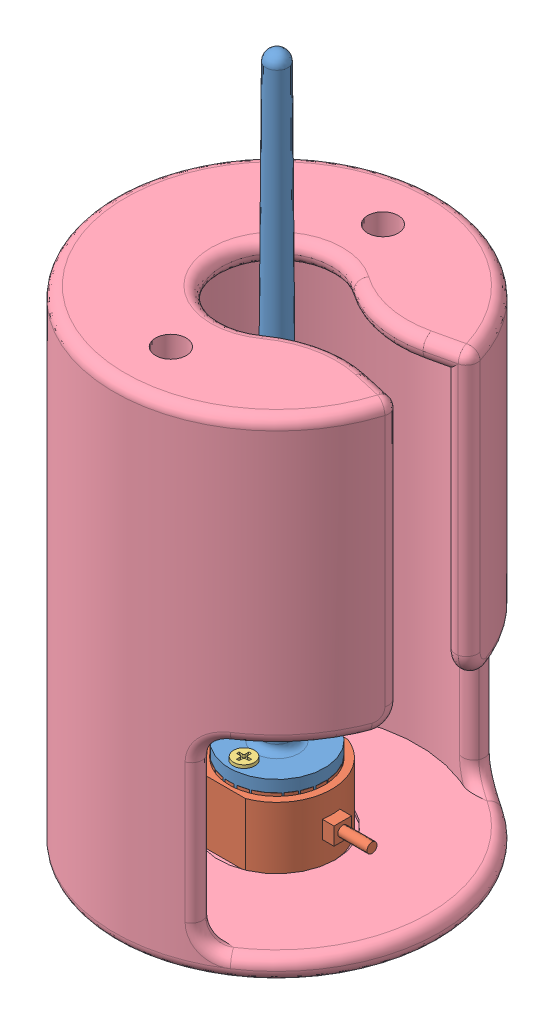
SolidWorks assembly 装配体1, configuration 默认. Lengths in mm.
Overall size (44.5 95.74 44.5).
7 component instances, 4 part files, 13 mates.
Components (placement in the parent):
- press_ indenter-1: press_ indenter [默认] at (-19.629 -24.15 83.9384) size (13 83.94 13)
- press_sensor-1: press_sensor [默认] at (-19.629 -32.75 83.9384) size (20.5 9.05 14)
- cross recessed cheese head screws type a gb-1: cross recessed cheese head screws type a gb [GB_CROSS_SCREWS_TYPE135 M2X5-N] at (-19.629 -21.6729 79.4384) x (0 -1 0) z (-0.546944 0 0.837169) size (5.7 2.98 2.98)
- cross recessed cheese head screws type a gb-2: cross recessed cheese head screws type a gb [GB_CROSS_SCREWS_TYPE135 M2X5-N] at (-19.629 -21.7499 88.4384) x (0 -1 0) z (0 0 1) size (5.7 2.98 2.98)
- press_outer-1: press_outer [默认] at (-19.629 -35.25 83.9384) x (0 0 -1) z (1 0 0) size (44.5 67 44.5)
- cross recessed cheese head screws type a gb-3: cross recessed cheese head screws type a gb [GB_CROSS_SCREWS_TYPE135 M2X5-N] at (-19.629 -35.95 79.4384) x (0 1 0) z (0 0 1) size (5.7 2.98 2.98)
- cross recessed cheese head screws type a gb-5: cross recessed cheese head screws type a gb [GB_CROSS_SCREWS_TYPE135 M2X5-N] at (-19.629 -35.95 88.4384) x (0 1 0) z (0.864517 0 0.502603) size (5.7 2.98 2.98)
Mates (geometry in assembly coordinates):
- 同心1: concentric aligned: cylinder of press_ indenter-1 through (-19.629 -24.15 88.4384) axis (0 1 0) radius 1.1; circle of press_sensor-1
- 重合3: coincident aligned: plane of press_ indenter-1; plane of press_sensor-1 through (-19.629 -24.15 83.9384) normal (0 1 0)
- 同心2: concentric aligned: circle of press_ indenter-1; circle of press_sensor-1
- 同心4: concentric anti-aligned: circle of press_ indenter-1; circle of cross recessed cheese head screws type a gb-2
- 同心5: concentric aligned: circle of press_ indenter-1; circle of cross recessed cheese head screws type a gb-1
- 重合7: coincident anti-aligned: plane of press_sensor-1 through (-19.629 -32.75 83.9384) normal (0 -1 0); plane of press_outer-1 through (-19.629 -32.75 83.9384) normal (0 1 0)
- 同心6: concentric aligned: circle of press_sensor-1; circle of press_outer-1
- 同心7: concentric aligned: circle of press_sensor-1; circle of press_outer-1
- 重合8: coincident: plane of press_outer-1 through (-19.629 -35.25 83.9384) normal (0 -1 0); plane of cross recessed cheese head screws type a gb-3 through (-19.629 -35.25 79.4384) normal (0 1 0)
- 重合9: coincident: plane of press_outer-1 through (-19.629 -35.25 83.9384) normal (0 -1 0); plane of cross recessed cheese head screws type a gb-3 through (-19.629 -35.25 79.4384) normal (0 1 0)
- 同心8: concentric aligned: circle of press_outer-1; circle of cross recessed cheese head screws type a gb-3
- 同心9: concentric: circle of press_outer-1; circle of cross recessed cheese head screws type a gb-5
- 重合11: coincident anti-aligned: plane of press_outer-1 through (-19.629 -35.25 83.9384) normal (0 -1 0); plane of cross recessed cheese head screws type a gb-5 through (-19.629 -35.25 88.4384) normal (0 1 0)
